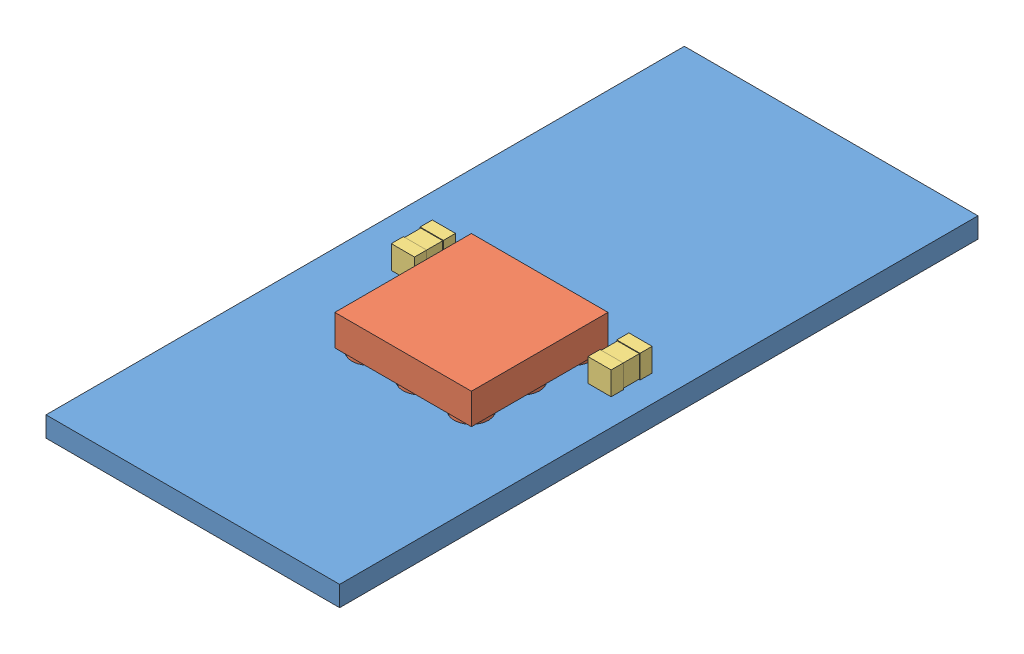
SolidWorks assembly IRS3_DC, configuration Default. Lengths in mm.
Overall size (23 4.24 50).
4 component instances, 3 part files, 2 mates.
Components (placement in the parent):
- IRS3_DC.revA-1: IRS3_DC.revA [Default] at origin size (23 1.59 50)
- IRS3_DC.heatsink-2: IRS3_DC.heatsink [Default] at (0 0.24 0) size (24 4 11.5)
- 1206.inductor-1: 1206.inductor [Default] at (20 1.5875 -24.96) size (1.82 1.82 3.21)
- 1206.inductor-2: 1206.inductor [Default] at (4.64 1.5875 -24.92) size (1.82 1.82 3.21)
Mates (geometry in assembly coordinates):
- Coincident4: coincident aligned: plane of IRS3_DC.revA-1 through (0 1.5875 -50) normal (0 1 0); plane of 1206.inductor-1
- Coincident6: coincident aligned: plane of IRS3_DC.revA-1 through (0 1.5875 -50) normal (0 1 0); plane of 1206.inductor-2
